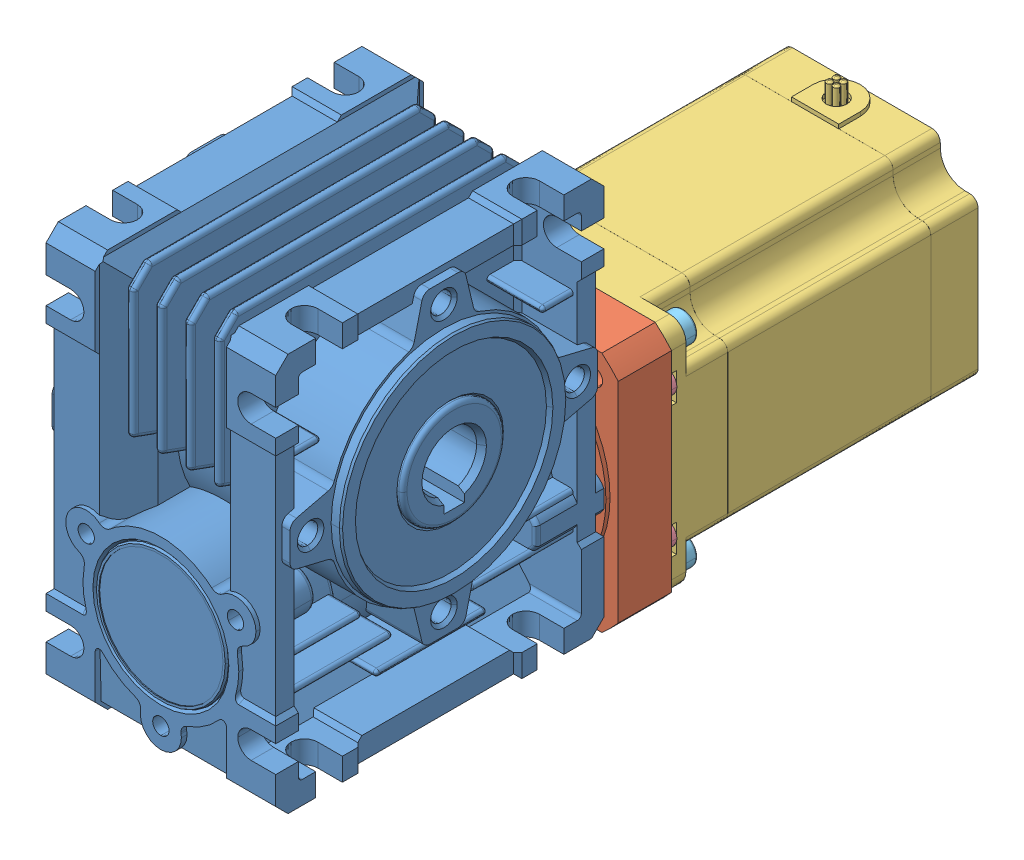
SolidWorks assembly mOTOR, configuration Default. Lengths in mm.
Overall size (63 99.5 171.76).
13 component instances, 5 part files, 0 mates.
Components (placement in the parent):
- 57HS74..0 .STEP-1: 57HS74..0 .STEP [Default] at origin size (63 99.5 171.76)
  - JMRV030+182________9__.STEP.STEP-1: JMRV030+182________9__.STEP.STEP [Default] at (107.0724 75.4426 266.1235) x (0 0 -1) z (-1 0 0) size (95.75 99.5 63)
    - JMRV030__9__.STEP.STEP-1: JMRV030__9__.STEP.STEP [Default] at (37.8735 8.9192 110) size (90.75 97 63)
    - F30-182______.STEP.STEP-1: F30-182______.STEP.STEP [Default] at (31.8735 8.9192 110) size (20 59 59)
  - 57HS7407-23J3-500.STEP-1: 57HS7407-23J3-500.STEP [Default] at (-2.9276 66.5235 138.25) size (56.4 61.4 99.01)
  - cross recessed pan head screws gb_GB_CROSS_SCREWS_TYPE1 M3X30-30  H type-N.STEP-1: cross recessed pan head screws gb_GB_CROSS_SCREWS_TYPE1 M3X30-30  H type-N.STEP [Default] at (-28.4276 50.5235 214.15) x (0 0 -1) z (1 0 0) size (32.39 5.6 5.6)
  - cross recessed pan head screws gb_GB_CROSS_SCREWS_TYPE1 M3X30-30  H type-N.STEP-2: cross recessed pan head screws gb_GB_CROSS_SCREWS_TYPE1 M3X30-30  H type-N.STEP [Default] at (-28.4276 82.5235 214.15) x (0 0 -1) z (1 0 0) size (32.39 5.6 5.6)
  - cross recessed pan head screws gb_GB_CROSS_SCREWS_TYPE1 M3X30-30  H type-N.STEP-3: cross recessed pan head screws gb_GB_CROSS_SCREWS_TYPE1 M3X30-30  H type-N.STEP [Default] at (22.5724 50.5235 214.15) x (0 0 -1) z (1 0 0) size (32.39 5.6 5.6)
  - cross recessed pan head screws gb_GB_CROSS_SCREWS_TYPE1 M3X30-30  H type-N.STEP-4: cross recessed pan head screws gb_GB_CROSS_SCREWS_TYPE1 M3X30-30  H type-N.STEP [Default] at (22.5724 82.5235 214.15) x (0 0 -1) z (1 0 0) size (32.39 5.6 5.6)
  - hexagon socket head cap screws gb_GB_FASTENER_SCREWS_HSHCS M4X6-N.STEP-1: hexagon socket head cap screws gb_GB_FASTENER_SCREWS_HSHCS M4X6-N.STEP [Default] at (20.6574 90.1085 205.45) x (0 0 1) z (-1 0 0) size (10 7 7)
  - hexagon socket head cap screws gb_GB_FASTENER_SCREWS_HSHCS M4X6-N.STEP-2: hexagon socket head cap screws gb_GB_FASTENER_SCREWS_HSHCS M4X6-N.STEP [Default] at (-26.5126 90.1085 205.45) x (0 0 1) z (-1 0 0) size (10 7 7)
  - hexagon socket head cap screws gb_GB_FASTENER_SCREWS_HSHCS M4X6-N.STEP-3: hexagon socket head cap screws gb_GB_FASTENER_SCREWS_HSHCS M4X6-N.STEP [Default] at (20.6574 42.9385 205.45) x (0 0 1) z (-1 0 0) size (10 7 7)
  - hexagon socket head cap screws gb_GB_FASTENER_SCREWS_HSHCS M4X6-N.STEP-4: hexagon socket head cap screws gb_GB_FASTENER_SCREWS_HSHCS M4X6-N.STEP [Default] at (-26.5126 42.9385 205.45) x (0 0 1) z (-1 0 0) size (10 7 7)
